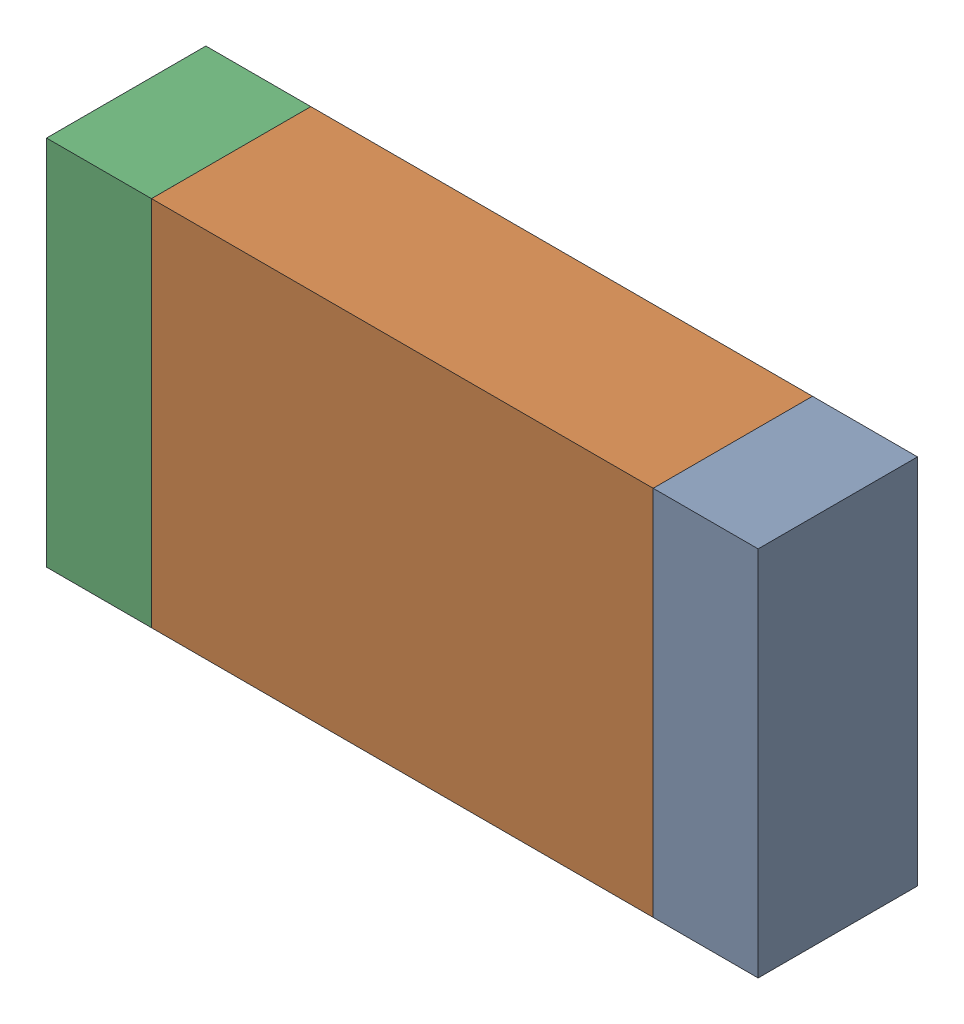
SolidWorks assembly R01-2, configuration Default. Lengths in mm.
Overall size (3.35 1.75 0.75).
6 component instances, 2 part files, 0 mates.
Components (placement in the parent):
- 959206760-2-1: 959206760-2 [Default] at (117.3285 91.9479 0) size (0.49 1.75 0.75)
  - Extruded-64-1: Extruded-64 [Default] at origin size (0.49 1.75 0.75)
- 959206896-2-1: 959206896-2 [Default] at (115.901 91.9479 0) size (2.36 1.75 0.75)
  - Extruded-65-1: Extruded-65 [Default] at origin size (2.36 1.75 0.75)
- 959206760-2-2: 959206760-2 [Default] at (114.4735 91.9479 0) size (0.49 1.75 0.75)
  - Extruded-64-1: Extruded-64 [Default] at origin size (0.49 1.75 0.75)
